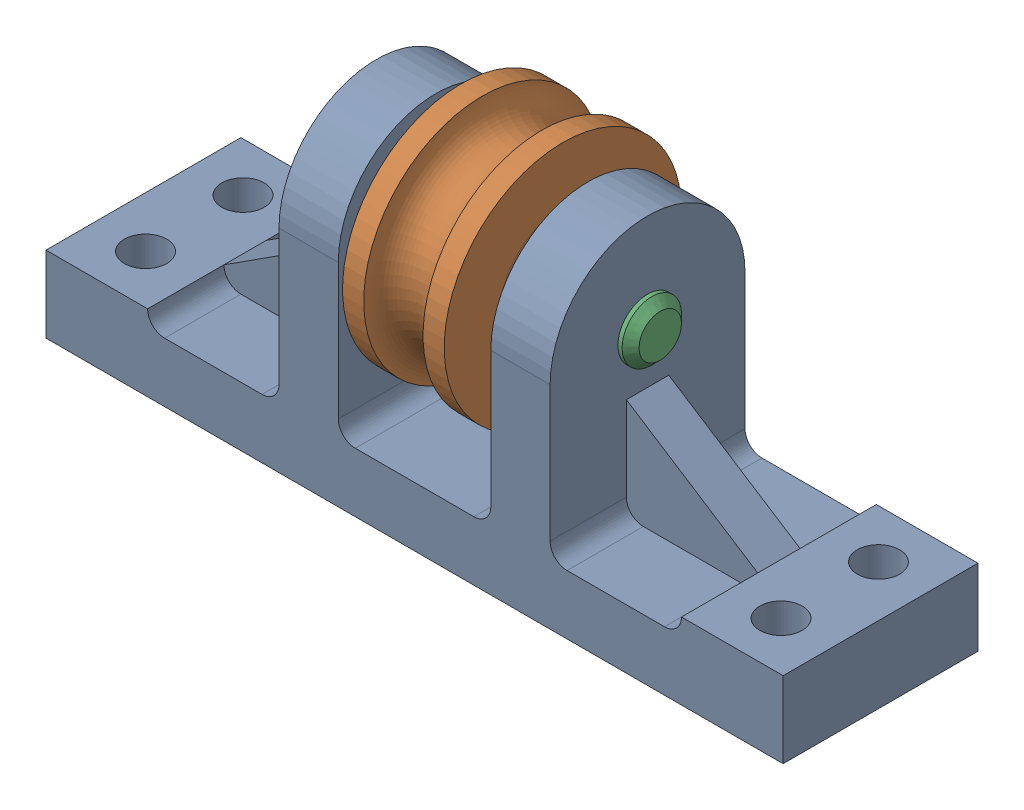
SolidWorks assembly Assem3, configuration Default. Lengths in mm.
Overall size (174 88.15 76.31).
3 component instances, 3 part files, 4 mates.
Components (placement in the parent):
- obj1-1: obj1 [Default] at (6.0586 -22.2015 11.8863) size (174 73 46)
- obj2-1: obj2 [Default] at (-7.9414 21.705 15.3315) x (1 0 0) z (0 0.870502 -0.492165) size (28 56 56)
- obj3-1: obj3 [Default] at (6.0586 27.7985 11.8863) x (0 0.503614 0.863929) z (-1 0 0) size (14 14 70)
Mates (geometry in assembly coordinates):
- Concentric1: concentric anti-aligned: circle of obj1-1; circle of obj3-1
- Concentric2: concentric aligned: circle of obj1-1; circle of obj2-1
- Coincident3: coincident aligned: plane of obj3-1 through (-28.9414 27.7985 11.8863) normal (-1 0 0)
- Coincident4: coincident aligned: plane of obj2-1 through (-7.9414 20.1746 1.3566) normal (-1 0 0)
